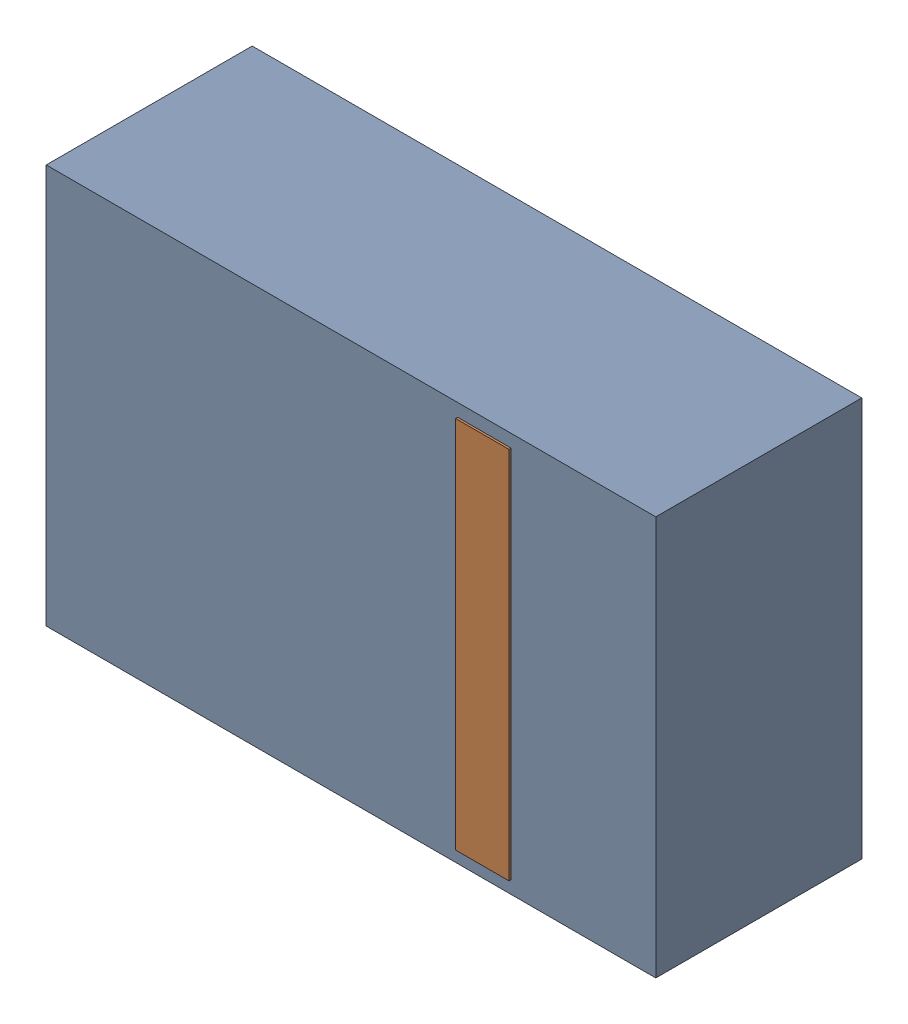
SolidWorks assembly D22, configuration Default. Lengths in mm.
Overall size (2.9 1.9 0.99).
4 component instances, 2 part files, 0 mates.
Components (placement in the parent):
- 905269392-1: 905269392 [Default] at (97.663 72.898 0) size (2.9 1.9 0.98)
  - Extruded_5-1: Extruded_5 [Default] at origin size (2.9 1.9 0.98)
- 905269800-1: 905269800 [Default] at (98.298 72.898 0.95) size (0.25 1.78 0.04)
  - Extruded_6-1: Extruded_6 [Default] at origin size (0.25 1.78 0.04)
